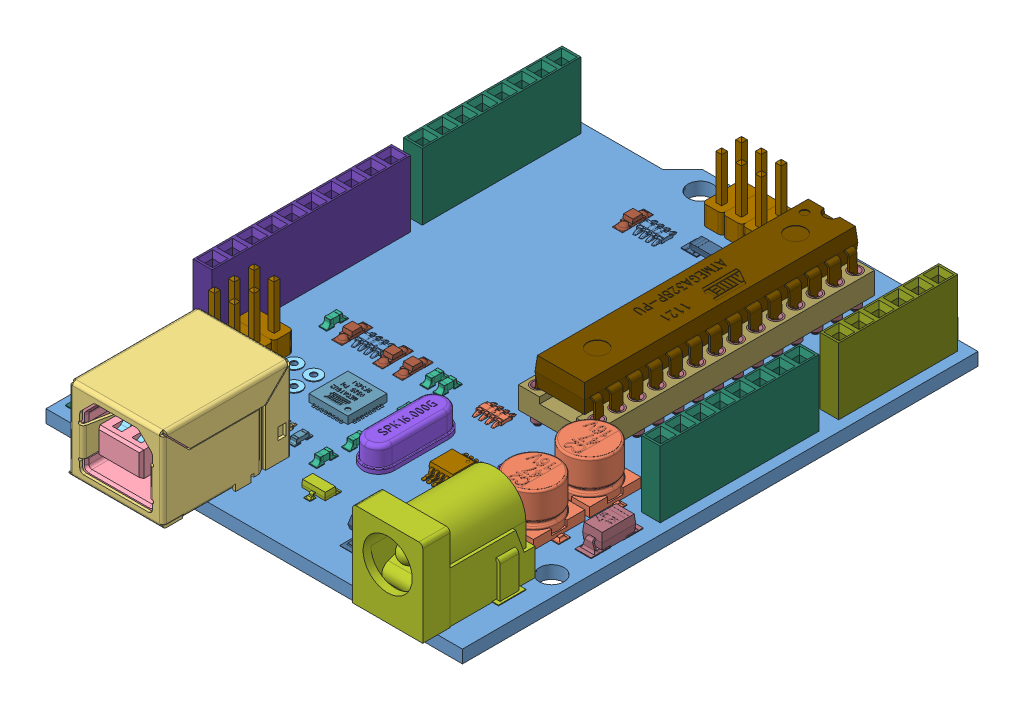
SolidWorks assembly User Library-arduino_uno, configuration Default. Lengths in mm.
Overall size (53.34 15.25 74.93).
83 component instances, 34 part files, 0 mates.
Components (placement in the parent):
- User Library-arduino_uno_unoboard blue-1: User Library-arduino_uno_unoboard blue [Default] at origin size (53.34 1.65 68.58)
- User Library-arduino_uno_47uf CAP Dcase-1: User Library-arduino_uno_47uf CAP Dcase [Default] at (-9.4141 0 -18.4991) x (0 0 -1) z (1 0 0) size (6.6 5.81 8)
- User Library-arduino_uno_USB SHELL-1: User Library-arduino_uno_USB SHELL [Default] at (-38.02 0.43 6.35) size (13.72 15.2 16.51)
- User Library-arduino_uno_USB core-1: User Library-arduino_uno_USB core [Default] at (-38.02 0.43 6.35) size (11.3 10.68 15.75)
- User Library-arduino_uno_usb top contact-1: User Library-arduino_uno_usb top contact [Default] at (-36.77 6.52 5.97) size (1 9.67 13.76)
- User Library-arduino_uno_usb btm contact-1: User Library-arduino_uno_usb btm contact [Default] at (-36.77 4.84 5.97) size (1 6.84 11.76)
- User Library-arduino_uno_usb btm contact-2: User Library-arduino_uno_usb btm contact [Default] at (-39.27 4.84 5.97) size (1 6.84 11.76)
- User Library-arduino_uno_usb top contact-2: User Library-arduino_uno_usb top contact [Default] at (-39.27 6.52 5.97) size (1 9.67 13.76)
- User Library-arduino_uno_power jack-1: User Library-arduino_uno_power jack [Default] at (-7.675 0 1.905) size (11.2 15.2 15.9)
- User Library-arduino_uno_47uf CAP Dcase-2: User Library-arduino_uno_47uf CAP Dcase [Default] at (-9.4141 0 -25.7132) x (0 0 -1) z (1 0 0) size (6.6 5.81 8)
- User Library-arduino_uno_crystal-1: User Library-arduino_uno_crystal [Default] at (-26.162 0 -18.923) x (1 0 0) z (0 0 -1) size (4 5 11)
- User Library-arduino_uno_2pin_header__02-1: User Library-arduino_uno_2pin_header__02 [Default] at (-46.23 0 -15.75) size (5 11.75 2.54)
- User Library-arduino_uno_nano - reg-1: User Library-arduino_uno_nano - reg [Default] at (-17.399 0 -7.747) size (6.5 1.69 8.3)
- User Library-arduino_uno_led-1: User Library-arduino_uno_led [Default] at (-34.29 0 -27.94) x (0 0 1) z (-1 0 0) size (4 0.9 1.55)
- User Library-arduino_uno_2pin_header__02-2: User Library-arduino_uno_2pin_header__02 [Default] at (-30.43 0 -64.91) x (0 0 1) z (-1 0 0) size (5 11.75 2.54)
- User Library-arduino_uno_dip28-1: User Library-arduino_uno_dip28 [Default] at (-16.383 1.5 -46.355) x (0 0 -1) z (1 0 0) size (35.48 2.8 10.1)
- User Library-arduino_uno_dip socket pin-1: User Library-arduino_uno_dip socket pin [Default] at (-20.193 4.3 -62.865) x (0 0 -1) z (1 0 0) size (1.7 7.37 1.7)
- User Library-arduino_uno_dip socket pin-2: User Library-arduino_uno_dip socket pin [Default] at (-12.573 4.3 -62.865) x (0 0 -1) z (1 0 0) size (1.7 7.37 1.7)
- User Library-arduino_uno_dip socket pin-3: User Library-arduino_uno_dip socket pin [Default] at (-20.193 4.3 -60.325) x (0 0 -1) z (1 0 0) size (1.7 7.37 1.7)
- User Library-arduino_uno_dip socket pin-4: User Library-arduino_uno_dip socket pin [Default] at (-12.573 4.3 -60.325) x (0 0 -1) z (1 0 0) size (1.7 7.37 1.7)
- User Library-arduino_uno_dip socket pin-5: User Library-arduino_uno_dip socket pin [Default] at (-20.193 4.3 -57.785) x (0 0 -1) z (1 0 0) size (1.7 7.37 1.7)
- User Library-arduino_uno_dip socket pin-6: User Library-arduino_uno_dip socket pin [Default] at (-12.573 4.3 -57.785) x (0 0 -1) z (1 0 0) size (1.7 7.37 1.7)
- User Library-arduino_uno_dip socket pin-7: User Library-arduino_uno_dip socket pin [Default] at (-20.193 4.3 -55.245) x (0 0 -1) z (1 0 0) size (1.7 7.37 1.7)
- User Library-arduino_uno_dip socket pin-8: User Library-arduino_uno_dip socket pin [Default] at (-12.573 4.3 -55.245) x (0 0 -1) z (1 0 0) size (1.7 7.37 1.7)
- User Library-arduino_uno_dip socket pin-9: User Library-arduino_uno_dip socket pin [Default] at (-20.193 4.3 -52.705) x (0 0 -1) z (1 0 0) size (1.7 7.37 1.7)
- User Library-arduino_uno_dip socket pin-10: User Library-arduino_uno_dip socket pin [Default] at (-12.573 4.3 -52.705) x (0 0 -1) z (1 0 0) size (1.7 7.37 1.7)
- User Library-arduino_uno_dip socket pin-11: User Library-arduino_uno_dip socket pin [Default] at (-20.193 4.3 -50.165) x (0 0 -1) z (1 0 0) size (1.7 7.37 1.7)
- User Library-arduino_uno_dip socket pin-12: User Library-arduino_uno_dip socket pin [Default] at (-12.573 4.3 -50.165) x (0 0 -1) z (1 0 0) size (1.7 7.37 1.7)
- User Library-arduino_uno_dip socket pin-13: User Library-arduino_uno_dip socket pin [Default] at (-20.193 4.3 -47.625) x (0 0 -1) z (1 0 0) size (1.7 7.37 1.7)
- User Library-arduino_uno_dip socket pin-14: User Library-arduino_uno_dip socket pin [Default] at (-12.573 4.3 -47.625) x (0 0 -1) z (1 0 0) size (1.7 7.37 1.7)
- User Library-arduino_uno_dip socket pin-15: User Library-arduino_uno_dip socket pin [Default] at (-20.193 4.3 -45.085) x (0 0 -1) z (1 0 0) size (1.7 7.37 1.7)
- User Library-arduino_uno_dip socket pin-16: User Library-arduino_uno_dip socket pin [Default] at (-12.573 4.3 -45.085) x (0 0 -1) z (1 0 0) size (1.7 7.37 1.7)
- User Library-arduino_uno_dip socket pin-17: User Library-arduino_uno_dip socket pin [Default] at (-20.193 4.3 -42.545) x (0 0 -1) z (1 0 0) size (1.7 7.37 1.7)
- User Library-arduino_uno_dip socket pin-18: User Library-arduino_uno_dip socket pin [Default] at (-12.573 4.3 -42.545) x (0 0 -1) z (1 0 0) size (1.7 7.37 1.7)
- User Library-arduino_uno_dip socket pin-19: User Library-arduino_uno_dip socket pin [Default] at (-20.193 4.3 -40.005) x (0 0 -1) z (1 0 0) size (1.7 7.37 1.7)
- User Library-arduino_uno_dip socket pin-20: User Library-arduino_uno_dip socket pin [Default] at (-12.573 4.3 -40.005) x (0 0 -1) z (1 0 0) size (1.7 7.37 1.7)
- User Library-arduino_uno_dip socket pin-21: User Library-arduino_uno_dip socket pin [Default] at (-20.193 4.3 -37.465) x (0 0 -1) z (1 0 0) size (1.7 7.37 1.7)
- User Library-arduino_uno_dip socket pin-22: User Library-arduino_uno_dip socket pin [Default] at (-12.573 4.3 -37.465) x (0 0 -1) z (1 0 0) size (1.7 7.37 1.7)
- User Library-arduino_uno_dip socket pin-23: User Library-arduino_uno_dip socket pin [Default] at (-20.193 4.3 -34.925) x (0 0 -1) z (1 0 0) size (1.7 7.37 1.7)
- User Library-arduino_uno_dip socket pin-24: User Library-arduino_uno_dip socket pin [Default] at (-12.573 4.3 -34.925) x (0 0 -1) z (1 0 0) size (1.7 7.37 1.7)
- User Library-arduino_uno_dip socket pin-25: User Library-arduino_uno_dip socket pin [Default] at (-20.193 4.3 -32.385) x (0 0 -1) z (1 0 0) size (1.7 7.37 1.7)
- User Library-arduino_uno_dip socket pin-26: User Library-arduino_uno_dip socket pin [Default] at (-12.573 4.3 -32.385) x (0 0 -1) z (1 0 0) size (1.7 7.37 1.7)
- User Library-arduino_uno_dip socket pin-27: User Library-arduino_uno_dip socket pin [Default] at (-20.193 4.3 -29.845) x (0 0 -1) z (1 0 0) size (1.7 7.37 1.7)
- User Library-arduino_uno_dip socket pin-28: User Library-arduino_uno_dip socket pin [Default] at (-12.573 4.3 -29.845) x (0 0 -1) z (1 0 0) size (1.7 7.37 1.7)
- User Library-arduino_uno_2pin_header__02-3: User Library-arduino_uno_2pin_header__02 [Default] at (-27.89 0 -64.91) x (0 0 1) z (-1 0 0) size (5 11.75 2.54)
- User Library-arduino_uno_2pin_header__02-4: User Library-arduino_uno_2pin_header__02 [Default] at (-25.35 0 -64.91) x (0 0 1) z (-1 0 0) size (5 11.75 2.54)
- User Library-arduino_uno_2pin_header__02-5: User Library-arduino_uno_2pin_header__02 [Default] at (-46.23 0 -18.29) size (5 11.75 2.54)
- User Library-arduino_uno_2pin_header__02-6: User Library-arduino_uno_2pin_header__02 [Default] at (-46.23 0 -20.83) size (5 11.75 2.54)
- User Library-arduino_uno_atmega16u2-1: User Library-arduino_uno_atmega16u2 [Default] at (-34.671 0.06 -20) x (1 0 0) z (0 0 -1) size (5.5 1.01 5.5)
- User Library-arduino_uno_led-2: User Library-arduino_uno_led [Default] at (-36.83 0 -27.94) x (0 0 1) z (-1 0 0) size (4 0.9 1.55)
- User Library-arduino_uno_led-3: User Library-arduino_uno_led [Default] at (-42.037 0 -27.94) x (0 0 1) z (-1 0 0) size (4 0.9 1.55)
- User Library-arduino_uno_led-4: User Library-arduino_uno_led [Default] at (-36.576 0 -58.42) x (0 0 1) z (-1 0 0) size (4 0.9 1.55)
- User Library-arduino_uno_8 PORT HEADER-1: User Library-arduino_uno_8 PORT HEADER [Default] at (-50.8 0 -45.72) x (0 0 -1) z (1 0 0) size (20.32 10.51 2.41)
- User Library-arduino_uno_8 PORT HEADER-2: User Library-arduino_uno_8 PORT HEADER [Default] at (-2.54 0 -27.94) x (0 0 -1) z (1 0 0) size (20.32 10.51 2.41)
- User Library-arduino_uno_6 PORT HEADER-1: User Library-arduino_uno_6 PORT HEADER [Default] at (-2.54 0 -50.8) x (0 0 -1) z (1 0 0) size (15.24 10.51 2.41)
- User Library-arduino_uno_10 PORT HEADER-1: User Library-arduino_uno_10 PORT HEADER [Default] at (-50.8 0 -18.796) x (0 0 -1) z (1 0 0) size (25.4 10.51 2.41)
- User Library-arduino_uno_ATMEL328P-1: User Library-arduino_uno_ATMEL328P [Default] at (-16.383 4.3 -46.355) x (0 0 -1) z (1 0 0) size (35 7.27 7.87)
- User Library-arduino_uno_102 RESISTOR PACK-1: User Library-arduino_uno_102 RESISTOR PACK [Default] at (-33.782 0 -58.42) size (3.2 0.51 3)
- User Library-arduino_uno_102 RESISTOR PACK-2: User Library-arduino_uno_102 RESISTOR PACK [Default] at (-39.37 0 -27.94) size (3.2 0.51 3)
- User Library-arduino_uno_103 RESISTOR PACK-1: User Library-arduino_uno_103 RESISTOR PACK [Default] at (-23.876 0 -27.94) size (3.2 0.51 3)
- User Library-arduino_uno_220 RESISTOR PACK-1: User Library-arduino_uno_220 RESISTOR PACK [Default] at (-36.83 0 -12.827) size (3.2 0.51 3)
- User Library-arduino_uno_16mhz crystal - measured-1: User Library-arduino_uno_16mhz crystal - measured [Default] at (-24.892 0 -41.275) x (0 0 -1) z (1 0 0) size (3.4 0.8 2)
- User Library-arduino_uno_PADS001-1: User Library-arduino_uno_PADS001 [Default] at (-39.878 0.1 -18.288) x (-1 0 0) z (0 0 1) size (4.54 0.1 4.54)
- User Library-arduino_uno_603 cap on pad-1: User Library-arduino_uno_603 cap on pad [Default] at (-44.45 0 -27.94) x (0 0 -1) z (1 0 0) size (2.76 0.91 1.02)
- User Library-arduino_uno_ssot3-1: User Library-arduino_uno_ssot3 [Default] at (-26.5 0 -8.128) x (-1 0 0) z (0 0 -1) size (3 1.13 3.09)
- User Library-arduino_uno_603 cap on pad-2: User Library-arduino_uno_603 cap on pad [Default] at (-29.845 0 -27.94) x (0 0 -1) z (1 0 0) size (2.76 0.91 1.02)
- User Library-arduino_uno_603 cap on pad-3: User Library-arduino_uno_603 cap on pad [Default] at (-31.496 0 -27.94) x (0 0 -1) z (1 0 0) size (2.76 0.91 1.02)
- User Library-arduino_uno_lmv358-1: User Library-arduino_uno_lmv358 [Default] at (-15.24 0 -21.971) x (0 0 -1) z (1 0 0) size (3.7 1.4 2.9)
- User Library-arduino_uno_603 cap on pad-4: User Library-arduino_uno_603 cap on pad [Default] at (-15.24 0 -18.415) size (2.76 0.91 1.02)
- User Library-arduino_uno_603 cap on pad-5: User Library-arduino_uno_603 cap on pad [Default] at (-29.845 0 -12.065) x (0 0 1) z (-1 0 0) size (2.76 0.91 1.02)
- User Library-arduino_uno_603 cap on pad-6: User Library-arduino_uno_603 cap on pad [Default] at (-29.591 0 -22.352) x (0 0 1) z (-1 0 0) size (2.76 0.91 1.02)
- User Library-arduino_uno_603 cap on pad-7: User Library-arduino_uno_603 cap on pad [Default] at (-29.591 0 -16.002) x (0 0 1) z (-1 0 0) size (2.76 0.91 1.02)
- User Library-arduino_uno_603 cap on pad-8: User Library-arduino_uno_603 cap on pad [Default] at (-41.91 0 -12.7) x (0 0 1) z (-1 0 0) size (2.76 0.91 1.02)
- User Library-arduino_uno_lp2985dgkr-1: User Library-arduino_uno_lp2985dgkr [Default] at (-20.32 0 -19.05) x (0 0 -1) z (1 0 0) size (5.85 1.1 3)
- User Library-arduino_uno_cd1206 diode-1: User Library-arduino_uno_cd1206 diode [Default] at (-27.94 0 -59.436) x (0 0 -1) z (1 0 0) size (2.09 0.96 5)
- User Library-arduino_uno_cd1206 diode-2: User Library-arduino_uno_cd1206 diode [Default] at (-46.228 0 -13.081) x (0 0 1) z (-1 0 0) size (2.09 0.96 5)
- User Library-arduino_uno_603 resistor-1: User Library-arduino_uno_603 resistor [Default] at (-29.591 0 -19.05) x (0 0 1) z (-1 0 0) size (2.36 0.62 1.03)
- User Library-arduino_uno_blm21-1: User Library-arduino_uno_blm21 [Default] at (-45.085 0 -7.62) x (0 0 -1) z (1 0 0) size (2.78 0.95 1.32)
- User Library-arduino_uno_m7 diode-1: User Library-arduino_uno_m7 diode [Default] at (-2.794 0 -21.59) x (0 0 -1) z (1 0 0) size (6.66 2.35 2.5)
- User Library-arduino_uno_MLC0603-1: User Library-arduino_uno_MLC0603 [Default] at (-33.655 0 -12.827) x (0 0 -1) z (1 0 0) size (2.36 0.6 1.03)
- User Library-arduino_uno_MLC0603-2: User Library-arduino_uno_MLC0603 [Default] at (-39.37 0 -12.827) x (0 0 -1) z (1 0 0) size (2.36 0.6 1.03)
- User Library-arduino_uno_RESET CORE-1: User Library-arduino_uno_RESET CORE [Default] at (-49.403 0.1 -6.35) x (-1 0 0) z (0 0 -1) size (6.2 3.1 9.6)
- User Library-arduino_uno_RESET-1: User Library-arduino_uno_RESET [Default] at (-49.403 0.1 -6.35) x (0 0 1) z (-1 0 0) size (7.3 2 6.2)
